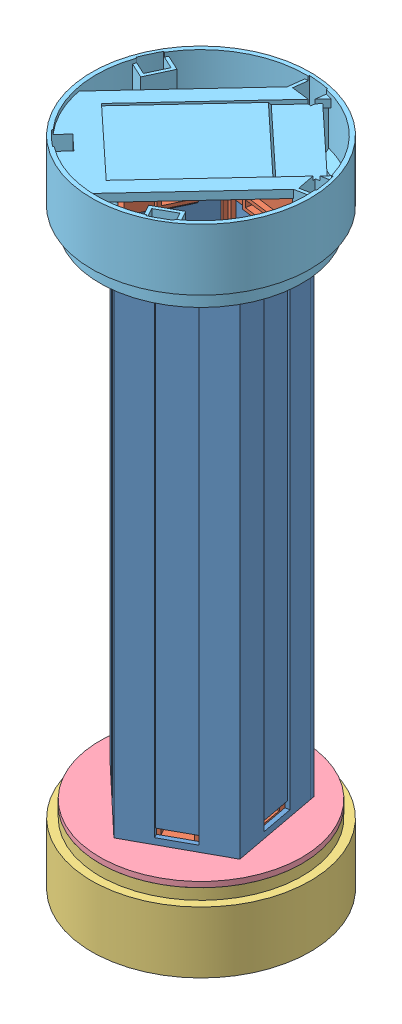
SolidWorks assembly Lamp, configuration Default. Lengths in mm.
Overall size (113.07 239.04 113.07).
5 component instances, 5 part files, 11 mates.
Components (placement in the parent):
- LED ring-1: LED ring [Default] at (0.0775 28.5 -0.3843) x (0.995333 0 0.096504) z (-0.096504 0 0.995333) size (54.99 182 52.83)
- Core-1: Core [Default] at (0 214.5 0) x (-0.987357 0 -0.158512) z (0 -1 0) size (55.15 55.15 193.6)
- Base-1: Base [Default] at origin size (80 26.5 84.21)
- Core connector-1: Core connector [Default] at (0 20.5 0) x (0.89196 0 -0.452115) z (0 -1 0) size (74 74 8)
- Top-1: Top [Default] at (0 239.0422 0) x (-0.731748 0 -0.681576) z (-0.681576 0 0.731748) size (80 28.5 80)
Mates (geometry in assembly coordinates):
- Coincident1: coordinate: point of Base-1
- Coincident2: coincident anti-aligned: plane of Base-1 through (0 26.5 0) normal (0 1 0); plane of Core connector-1 through (0 26.5 0) normal (0 -1 0)
- Coincident3: coincident aligned: line of Base-1 through (15.9 0 17.9) axis (0 0 -1); line of Core connector-1 through (0 26.5 0) axis (0 -1 0)
- Parallel1: parallel anti-aligned: plane of LED ring-1 through (0.0775 28.5 -0.3843) normal (0 -1 0); plane of Core connector-1 through (0 28.5 0) normal (0 1 0)
- Parallel2: parallel anti-aligned: line of LED ring-1 through (26.2208 28.5 11.9899) axis (-0.185166 0 -0.982707); line of Core connector-1 through (18.4902 28.5 -19.6013) axis (0.185166 0 0.982707)
- Coincident9: coincident anti-aligned: plane of LED ring-1 through (0.0775 28.5 -0.3843) normal (0 -1 0); plane of Core connector-1 through (0 28.5 0) normal (0 1 0)
- Coincident10: coincident anti-aligned: plane of LED ring-1 through (-3.3601 210.5 26.3418) normal (-0.479776 0 -0.877391); plane of Core-1 through (24.0206 24.5 11.3695) normal (0.479776 0 0.877391)
- Coincident11: coincident anti-aligned: plane of Core-1 through (15.3408 213.3422 35.7088) normal (0 1 0); plane of Top-1 through (0 213.3422 0) normal (0 -1 0)
- Coincident12: coincident aligned: line of Core-1 through (0 24.5 0) axis (0 -1 0); line of Base-1 through (5.6 0 26.5) axis (0 0 -1)
- Coincident13: coincident anti-aligned: plane of Core-1 through (0 26.5 0) normal (0 1 0); plane of Core connector-1 through (0 26.5 0) normal (0 -1 0)
- Coincident14: coincident anti-aligned: line of Core-1 through (0 24.5 0) axis (0 -1 0); line of Top-1 through (0 221.1422 0) axis (0 1 0)
